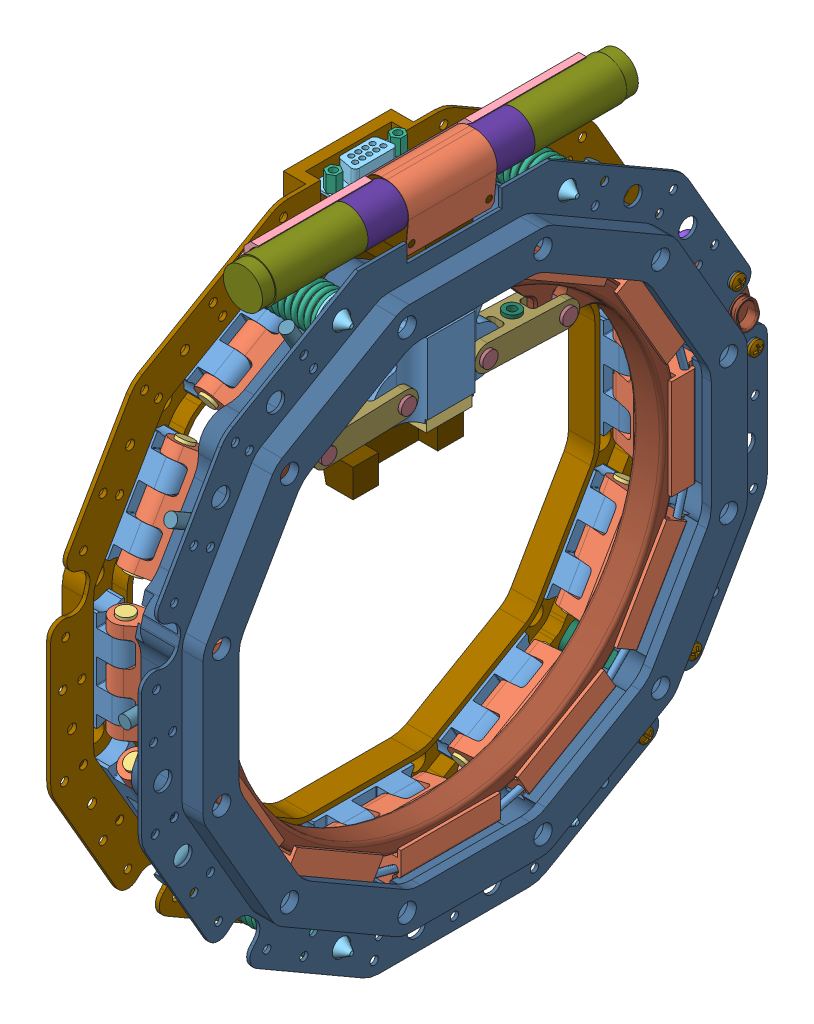
SolidWorks assembly T-01-00, configuration Default. Lengths in mm.
Overall size (53.34 255.61 245.22).
147 component instances, 37 part files, 0 mates.
Components (placement in the parent):
- 4000515 Rev A MLB 8.000-12 Assembly Simplified.STEP-1: 4000515 Rev A MLB 8.000-12 Assembly Simplified.STEP [Default] at origin size (53.34 255.61 245.22)
  - 4000519 MLB 8.000-12 Hinged Leaf Assembly SIMPLIFIED.STEP-1: 4000519 MLB 8.000-12 Hinged Leaf Assembly SIMPLIFIED.STEP [Default] at (4.318 84.9901 49.069) x (0 -0.5 0.866025) z (0 0.866025 0.5) size (40.89 39.6 18.1)
    - 4000391 Lower Hinge Link SIMPLIFIED.STEP-1: 4000391 Lower Hinge Link SIMPLIFIED.STEP [Default] at origin size (38.61 17.31 10.8)
    - 4000520 MLB 8.000-12 Upper Hinge Link SIMPLIFIED_Extrusion.STEP-1: 4000520 MLB 8.000-12 Upper Hinge Link SIMPLIFIED_Extrusion.STEP [Default] at (0 11.9126 0) size (38.61 33.09 18.1)
    - 4000369 Pin SIMPLIFIED.STEP-1: 4000369 Pin SIMPLIFIED.STEP [Default] at (0 11.9126 0) x (1 0 0) z (0 0 -1) size (40.89 6.31 6.31)
  - 4000307 Separation Spring Assembly SIMPLIFIED_Compressed.STEP-1: 4000307 Separation Spring Assembly SIMPLIFIED_Compressed.STEP [Default] at (10.16 -105.1143 -43.6767) x (0 -1 0) z (0 0 1) size (15.24 39.09 15.24)
    - 4000308 Separation Spring Lower Guide SIMPLIFIED.STEP-1: 4000308 Separation Spring Lower Guide SIMPLIFIED.STEP [Default] at origin size (15.24 31.34 15.24)
    - 4000309 Separation Spring Upper Guide SIMPLIFIED.STEP-1: 4000309 Separation Spring Upper Guide SIMPLIFIED.STEP [Default] at (0 2.286 0) size (15.24 36.8 15.24)
    - 0.60 OD x 0.072 Wire x 2.0 lg SST Spring SIMPLIFIED_Compressed.STEP-1: 0.60 OD x 0.072 Wire x 2.0 lg SST Spring SIMPLIFIED_Compressed.STEP [Default] at (0 3.1496 0) size (15.24 29.74 15.24)
    - 4000310 Separation Spring Pin SIMPLIFIED.STEP-1: 4000310 Separation Spring Pin SIMPLIFIED.STEP [Default] at (0 6.858 0) size (3.17 3.17 11.07)
  - 4000307 Separation Spring Assembly SIMPLIFIED_Compressed.STEP-2: 4000307 Separation Spring Assembly SIMPLIFIED_Compressed.STEP [Default] at (10.16 105.1143 -43.6767) x (0 -0.147249 -0.989099) z (0 -0.989099 0.147249) size (15.24 39.09 15.24)
    - 4000308 Separation Spring Lower Guide SIMPLIFIED.STEP-1: 4000308 Separation Spring Lower Guide SIMPLIFIED.STEP [Default] at origin size (15.24 31.34 15.24)
    - 4000309 Separation Spring Upper Guide SIMPLIFIED.STEP-1: 4000309 Separation Spring Upper Guide SIMPLIFIED.STEP [Default] at (0 2.286 0) size (15.24 36.8 15.24)
    - 0.60 OD x 0.072 Wire x 2.0 lg SST Spring SIMPLIFIED_Compressed.STEP-1: 0.60 OD x 0.072 Wire x 2.0 lg SST Spring SIMPLIFIED_Compressed.STEP [Default] at (0 3.1496 0) size (15.24 29.74 15.24)
    - 4000310 Separation Spring Pin SIMPLIFIED.STEP-1: 4000310 Separation Spring Pin SIMPLIFIED.STEP [Default] at (0 6.858 0) size (3.17 3.17 11.07)
  - 4000106 Lower Separation Connector SIMPLIFIED.STEP-1: 4000106 Lower Separation Connector SIMPLIFIED.STEP [Default] at (10.16 29.9775 -111.8774) x (0 -0.965926 -0.258819) z (0 0.258819 -0.965926) size (37.44 22.67 15.21)
    - 4000101 Lower Housing SIMPLIFIED.STEP-1: 4000101 Lower Housing SIMPLIFIED.STEP [Default] at origin size (37.44 21.64 15.21)
    - MS51957-14, 0.112-40 x 0.31 PNH Screw SIMPLIFIED.STEP-1: MS51957-14, 0.112-40 x 0.31 PNH Screw SIMPLIFIED.STEP [Default] at (-13.2461 4.1148 0) size (5.46 9.87 5.46)
    - MS51957-14, 0.112-40 x 0.31 PNH Screw SIMPLIFIED.STEP-2: MS51957-14, 0.112-40 x 0.31 PNH Screw SIMPLIFIED.STEP [Default] at (13.2461 4.1148 0) size (5.46 9.87 5.46)
    - NAS620C4, 0.115 x 0.209 x 0.032 Washer SIMPLIFIED.STEP-1: NAS620C4, 0.115 x 0.209 x 0.032 Washer SIMPLIFIED.STEP [Default] at (13.2461 1.27 0) size (5.31 0.81 5.31)
    - NAS620C4, 0.115 x 0.209 x 0.032 Washer SIMPLIFIED.STEP-2: NAS620C4, 0.115 x 0.209 x 0.032 Washer SIMPLIFIED.STEP [Default] at (-13.2461 1.27 0) size (5.31 0.81 5.31)
  - 4000107 Upper Separation Connector SIMPLIFIED.STEP-1: 4000107 Upper Separation Connector SIMPLIFIED.STEP [Default] at (49.8205 29.9775 -111.8774) x (0 0.965926 0.258819) z (0 0.258819 -0.965926) size (37.44 22.31 15.21)
    - 4000102 Upper Housing SIMPLIFIED.STEP-1: 4000102 Upper Housing SIMPLIFIED.STEP [Default] at (0 -5.8023 0) size (37.44 21.29 15.21)
    - MS51957-14, 0.112-40 x 0.31 PNH Screw SIMPLIFIED.STEP-1: MS51957-14, 0.112-40 x 0.31 PNH Screw SIMPLIFIED.STEP [Default] at (-13.2461 -1.6875 0) size (5.46 9.87 5.46)
    - MS51957-14, 0.112-40 x 0.31 PNH Screw SIMPLIFIED.STEP-2: MS51957-14, 0.112-40 x 0.31 PNH Screw SIMPLIFIED.STEP [Default] at (13.2461 -1.6875 0) x (0.987206 0 -0.159449) z (0.159449 0 0.987206) size (5.46 9.87 5.46)
    - NAS620C4, 0.115 x 0.209 x 0.032 Washer SIMPLIFIED.STEP-1: NAS620C4, 0.115 x 0.209 x 0.032 Washer SIMPLIFIED.STEP [Default] at (-13.2461 -4.5323 0) size (5.31 0.81 5.31)
    - NAS620C4, 0.115 x 0.209 x 0.032 Washer SIMPLIFIED.STEP-2: NAS620C4, 0.115 x 0.209 x 0.032 Washer SIMPLIFIED.STEP [Default] at (13.2461 -4.5323 0) size (5.31 0.81 5.31)
    - BG15L5-0.770-BEC-SOW-NKL-2, EMI Spring SIMPLIFIED.STEP-1: BG15L5-0.770-BEC-SOW-NKL-2, EMI Spring SIMPLIFIED.STEP [Default] at (0 -21.9313 0) size (35.89 2.03 13.67)
  - 4000383 Separation Switch Assembly SIMPLIFIED_Compressed.STEP-1: 4000383 Separation Switch Assembly SIMPLIFIED_Compressed.STEP [Default] at (44.0182 -78.5413 -78.5234) x (0 -0.707107 0.707107) z (0 -0.707107 -0.707107) size (33 44.21 11.81)
    - 4000350 Upper Switch Bracket SIMPLIFIED.STEP-1: 4000350 Upper Switch Bracket SIMPLIFIED.STEP [Default] at origin size (31.14 25.53 11.56)
    - MS24693-C27, 0.138-32 x 0.44 FLH Screw SIMPLIFIED.STEP-1: MS24693-C27, 0.138-32 x 0.44 FLH Screw SIMPLIFIED.STEP [Default] at (-6.35 20.701 11.4612) x (1 0 0) z (0 -1 0) size (6.35 11.11 6.35)
    - MS24693-C27, 0.138-32 x 0.44 FLH Screw SIMPLIFIED.STEP-2: MS24693-C27, 0.138-32 x 0.44 FLH Screw SIMPLIFIED.STEP [Default] at (6.35 20.701 11.4612) x (0.037732 -0.999288 0) z (-0.999288 -0.037732 0) size (6.35 11.11 6.35)
    - MS51957-14, 0.112-40 x 0.31 PNH Screw SIMPLIFIED.STEP-1: MS51957-14, 0.112-40 x 0.31 PNH Screw SIMPLIFIED.STEP [Default] at (13.2334 -4.1148 4.7625) x (-1 0 0) z (0 0 1) size (5.46 9.87 5.46)
    - MS51957-14, 0.112-40 x 0.31 PNH Screw SIMPLIFIED.STEP-2: MS51957-14, 0.112-40 x 0.31 PNH Screw SIMPLIFIED.STEP [Default] at (-13.2588 -4.1148 4.7625) x (0.837169 0 0.546944) z (0.546944 0 -0.837169) size (5.46 9.87 5.46)
    - NAS620C4, 0.115 x 0.209 x 0.032 Washer SIMPLIFIED.STEP-1: NAS620C4, 0.115 x 0.209 x 0.032 Washer SIMPLIFIED.STEP [Default] at (13.2334 -1.27 4.7625) x (-1 0 0) z (0 0 1) size (5.31 0.81 5.31)
    - NAS620C4, 0.115 x 0.209 x 0.032 Washer SIMPLIFIED.STEP-2: NAS620C4, 0.115 x 0.209 x 0.032 Washer SIMPLIFIED.STEP [Default] at (-13.2588 -1.27 4.7625) x (0.837169 0 0.546944) z (0.546944 0 -0.837169) size (5.31 0.81 5.31)
    - 65-401000 Switch SIMPLIFIED_Compressed Plunger.STEP-1: 65-401000 Switch SIMPLIFIED_Compressed Plunger.STEP [Default] at (0 23.0632 4.6355) size (21.59 38.91 9.78)
  - 4000519 MLB 8.000-12 Hinged Leaf Assembly SIMPLIFIED.STEP-2: 4000519 MLB 8.000-12 Hinged Leaf Assembly SIMPLIFIED.STEP [Default] at (4.318 49.069 84.9901) x (0 -0.866025 0.5) z (0 0.5 0.866025) size (40.89 39.6 18.1)
    - 4000391 Lower Hinge Link SIMPLIFIED.STEP-1: 4000391 Lower Hinge Link SIMPLIFIED.STEP [Default] at origin size (38.61 17.31 10.8)
    - 4000520 MLB 8.000-12 Upper Hinge Link SIMPLIFIED_Extrusion.STEP-1: 4000520 MLB 8.000-12 Upper Hinge Link SIMPLIFIED_Extrusion.STEP [Default] at (0 11.9126 0) size (38.61 33.09 18.1)
    - 4000369 Pin SIMPLIFIED.STEP-1: 4000369 Pin SIMPLIFIED.STEP [Default] at (0 11.9126 0) x (1 0 0) z (0 0 -1) size (40.89 6.31 6.31)
  - 4000519 MLB 8.000-12 Hinged Leaf Assembly SIMPLIFIED.STEP-3: 4000519 MLB 8.000-12 Hinged Leaf Assembly SIMPLIFIED.STEP [Default] at (4.318 0 98.1381) x (0 -1 0) z (0 0 1) size (40.89 39.6 18.1)
    - 4000391 Lower Hinge Link SIMPLIFIED.STEP-1: 4000391 Lower Hinge Link SIMPLIFIED.STEP [Default] at origin size (38.61 17.31 10.8)
    - 4000520 MLB 8.000-12 Upper Hinge Link SIMPLIFIED_Extrusion.STEP-1: 4000520 MLB 8.000-12 Upper Hinge Link SIMPLIFIED_Extrusion.STEP [Default] at (0 11.9126 0) size (38.61 33.09 18.1)
    - 4000369 Pin SIMPLIFIED.STEP-1: 4000369 Pin SIMPLIFIED.STEP [Default] at (0 11.9126 0) x (1 0 0) z (0 0 -1) size (40.89 6.31 6.31)
  - 4000519 MLB 8.000-12 Hinged Leaf Assembly SIMPLIFIED.STEP-4: 4000519 MLB 8.000-12 Hinged Leaf Assembly SIMPLIFIED.STEP [Default] at (4.318 -49.069 84.9901) x (0 -0.866025 -0.5) z (0 -0.5 0.866025) size (40.89 39.6 18.1)
    - 4000391 Lower Hinge Link SIMPLIFIED.STEP-1: 4000391 Lower Hinge Link SIMPLIFIED.STEP [Default] at origin size (38.61 17.31 10.8)
    - 4000520 MLB 8.000-12 Upper Hinge Link SIMPLIFIED_Extrusion.STEP-1: 4000520 MLB 8.000-12 Upper Hinge Link SIMPLIFIED_Extrusion.STEP [Default] at (0 11.9126 0) size (38.61 33.09 18.1)
    - 4000369 Pin SIMPLIFIED.STEP-1: 4000369 Pin SIMPLIFIED.STEP [Default] at (0 11.9126 0) x (1 0 0) z (0 0 -1) size (40.89 6.31 6.31)
  - 4000519 MLB 8.000-12 Hinged Leaf Assembly SIMPLIFIED.STEP-5: 4000519 MLB 8.000-12 Hinged Leaf Assembly SIMPLIFIED.STEP [Default] at (4.318 -84.9901 49.069) x (0 -0.5 -0.866025) z (0 -0.866025 0.5) size (40.89 39.6 18.1)
    - 4000391 Lower Hinge Link SIMPLIFIED.STEP-1: 4000391 Lower Hinge Link SIMPLIFIED.STEP [Default] at origin size (38.61 17.31 10.8)
    - 4000520 MLB 8.000-12 Upper Hinge Link SIMPLIFIED_Extrusion.STEP-1: 4000520 MLB 8.000-12 Upper Hinge Link SIMPLIFIED_Extrusion.STEP [Default] at (0 11.9126 0) size (38.61 33.09 18.1)
    - 4000369 Pin SIMPLIFIED.STEP-1: 4000369 Pin SIMPLIFIED.STEP [Default] at (0 11.9126 0) x (1 0 0) z (0 0 -1) size (40.89 6.31 6.31)
  - 4000519 MLB 8.000-12 Hinged Leaf Assembly SIMPLIFIED.STEP-6: 4000519 MLB 8.000-12 Hinged Leaf Assembly SIMPLIFIED.STEP [Default] at (4.318 -98.1381 0) x (0 0 -1) z (0 -1 0) size (40.89 39.6 18.1)
    - 4000391 Lower Hinge Link SIMPLIFIED.STEP-1: 4000391 Lower Hinge Link SIMPLIFIED.STEP [Default] at origin size (38.61 17.31 10.8)
    - 4000520 MLB 8.000-12 Upper Hinge Link SIMPLIFIED_Extrusion.STEP-1: 4000520 MLB 8.000-12 Upper Hinge Link SIMPLIFIED_Extrusion.STEP [Default] at (0 11.9126 0) size (38.61 33.09 18.1)
    - 4000369 Pin SIMPLIFIED.STEP-1: 4000369 Pin SIMPLIFIED.STEP [Default] at (0 11.9126 0) x (1 0 0) z (0 0 -1) size (40.89 6.31 6.31)
  - 4000519 MLB 8.000-12 Hinged Leaf Assembly SIMPLIFIED.STEP-7: 4000519 MLB 8.000-12 Hinged Leaf Assembly SIMPLIFIED.STEP [Default] at (4.318 -84.9901 -49.069) x (0 0.5 -0.866025) z (0 -0.866025 -0.5) size (40.89 39.6 18.1)
    - 4000391 Lower Hinge Link SIMPLIFIED.STEP-1: 4000391 Lower Hinge Link SIMPLIFIED.STEP [Default] at origin size (38.61 17.31 10.8)
    - 4000520 MLB 8.000-12 Upper Hinge Link SIMPLIFIED_Extrusion.STEP-1: 4000520 MLB 8.000-12 Upper Hinge Link SIMPLIFIED_Extrusion.STEP [Default] at (0 11.9126 0) size (38.61 33.09 18.1)
    - 4000369 Pin SIMPLIFIED.STEP-1: 4000369 Pin SIMPLIFIED.STEP [Default] at (0 11.9126 0) x (1 0 0) z (0 0 -1) size (40.89 6.31 6.31)
  - 4000519 MLB 8.000-12 Hinged Leaf Assembly SIMPLIFIED.STEP-8: 4000519 MLB 8.000-12 Hinged Leaf Assembly SIMPLIFIED.STEP [Default] at (4.318 -49.069 -84.9901) x (0 0.866025 -0.5) z (0 -0.5 -0.866025) size (40.89 39.6 18.1)
    - 4000391 Lower Hinge Link SIMPLIFIED.STEP-1: 4000391 Lower Hinge Link SIMPLIFIED.STEP [Default] at origin size (38.61 17.31 10.8)
    - 4000520 MLB 8.000-12 Upper Hinge Link SIMPLIFIED_Extrusion.STEP-1: 4000520 MLB 8.000-12 Upper Hinge Link SIMPLIFIED_Extrusion.STEP [Default] at (0 11.9126 0) size (38.61 33.09 18.1)
    - 4000369 Pin SIMPLIFIED.STEP-1: 4000369 Pin SIMPLIFIED.STEP [Default] at (0 11.9126 0) x (1 0 0) z (0 0 -1) size (40.89 6.31 6.31)
  - 4000519 MLB 8.000-12 Hinged Leaf Assembly SIMPLIFIED.STEP-9: 4000519 MLB 8.000-12 Hinged Leaf Assembly SIMPLIFIED.STEP [Default] at (4.318 0 -98.1381) x (0 1 0) z (0 0 -1) size (40.89 39.6 18.1)
    - 4000391 Lower Hinge Link SIMPLIFIED.STEP-1: 4000391 Lower Hinge Link SIMPLIFIED.STEP [Default] at origin size (38.61 17.31 10.8)
    - 4000520 MLB 8.000-12 Upper Hinge Link SIMPLIFIED_Extrusion.STEP-1: 4000520 MLB 8.000-12 Upper Hinge Link SIMPLIFIED_Extrusion.STEP [Default] at (0 11.9126 0) size (38.61 33.09 18.1)
    - 4000369 Pin SIMPLIFIED.STEP-1: 4000369 Pin SIMPLIFIED.STEP [Default] at (0 11.9126 0) x (1 0 0) z (0 0 -1) size (40.89 6.31 6.31)
  - 4000519 MLB 8.000-12 Hinged Leaf Assembly SIMPLIFIED.STEP-10: 4000519 MLB 8.000-12 Hinged Leaf Assembly SIMPLIFIED.STEP [Default] at (4.318 49.069 -84.9901) x (0 0.866025 0.5) z (0 0.5 -0.866025) size (40.89 39.6 18.1)
    - 4000391 Lower Hinge Link SIMPLIFIED.STEP-1: 4000391 Lower Hinge Link SIMPLIFIED.STEP [Default] at origin size (38.61 17.31 10.8)
    - 4000520 MLB 8.000-12 Upper Hinge Link SIMPLIFIED_Extrusion.STEP-1: 4000520 MLB 8.000-12 Upper Hinge Link SIMPLIFIED_Extrusion.STEP [Default] at (0 11.9126 0) size (38.61 33.09 18.1)
    - 4000369 Pin SIMPLIFIED.STEP-1: 4000369 Pin SIMPLIFIED.STEP [Default] at (0 11.9126 0) x (1 0 0) z (0 0 -1) size (40.89 6.31 6.31)
  - 4000519 MLB 8.000-12 Hinged Leaf Assembly SIMPLIFIED.STEP-11: 4000519 MLB 8.000-12 Hinged Leaf Assembly SIMPLIFIED.STEP [Default] at (4.318 84.9901 -49.069) x (0 0.5 0.866025) z (0 0.866025 -0.5) size (40.89 39.6 18.1)
    - 4000391 Lower Hinge Link SIMPLIFIED.STEP-1: 4000391 Lower Hinge Link SIMPLIFIED.STEP [Default] at origin size (38.61 17.31 10.8)
    - 4000520 MLB 8.000-12 Upper Hinge Link SIMPLIFIED_Extrusion.STEP-1: 4000520 MLB 8.000-12 Upper Hinge Link SIMPLIFIED_Extrusion.STEP [Default] at (0 11.9126 0) size (38.61 33.09 18.1)
    - 4000369 Pin SIMPLIFIED.STEP-1: 4000369 Pin SIMPLIFIED.STEP [Default] at (0 11.9126 0) x (1 0 0) z (0 0 -1) size (40.89 6.31 6.31)
  - 4000307 Separation Spring Assembly SIMPLIFIED_Compressed.STEP-3: 4000307 Separation Spring Assembly SIMPLIFIED_Compressed.STEP [Default] at (10.16 105.1143 43.6767) x (0 1 0) z (0 0 -1) size (15.24 39.09 15.24)
    - 4000308 Separation Spring Lower Guide SIMPLIFIED.STEP-1: 4000308 Separation Spring Lower Guide SIMPLIFIED.STEP [Default] at origin size (15.24 31.34 15.24)
    - 4000309 Separation Spring Upper Guide SIMPLIFIED.STEP-1: 4000309 Separation Spring Upper Guide SIMPLIFIED.STEP [Default] at (0 2.286 0) size (15.24 36.8 15.24)
    - 0.60 OD x 0.072 Wire x 2.0 lg SST Spring SIMPLIFIED_Compressed.STEP-1: 0.60 OD x 0.072 Wire x 2.0 lg SST Spring SIMPLIFIED_Compressed.STEP [Default] at (0 3.1496 0) size (15.24 29.74 15.24)
    - 4000310 Separation Spring Pin SIMPLIFIED.STEP-1: 4000310 Separation Spring Pin SIMPLIFIED.STEP [Default] at (0 6.858 0) size (3.17 3.17 11.07)
  - 4000307 Separation Spring Assembly SIMPLIFIED_Compressed.STEP-4: 4000307 Separation Spring Assembly SIMPLIFIED_Compressed.STEP [Default] at (10.16 -105.1143 43.6767) x (0 0.147249 0.989099) z (0 0.989099 -0.147249) size (15.24 39.09 15.24)
    - 4000308 Separation Spring Lower Guide SIMPLIFIED.STEP-1: 4000308 Separation Spring Lower Guide SIMPLIFIED.STEP [Default] at origin size (15.24 31.34 15.24)
    - 4000309 Separation Spring Upper Guide SIMPLIFIED.STEP-1: 4000309 Separation Spring Upper Guide SIMPLIFIED.STEP [Default] at (0 2.286 0) size (15.24 36.8 15.24)
    - 0.60 OD x 0.072 Wire x 2.0 lg SST Spring SIMPLIFIED_Compressed.STEP-1: 0.60 OD x 0.072 Wire x 2.0 lg SST Spring SIMPLIFIED_Compressed.STEP [Default] at (0 3.1496 0) size (15.24 29.74 15.24)
    - 4000310 Separation Spring Pin SIMPLIFIED.STEP-1: 4000310 Separation Spring Pin SIMPLIFIED.STEP [Default] at (0 6.858 0) size (3.17 3.17 11.07)
  - 4000433 F  Motor Bracket Assy Simple SIMPLIFIED.STEP-1: 4000433 F  Motor Bracket Assy Simple SIMPLIFIED.STEP [Default] at (4.318 98.5445 0) x (0 0 -1) z (0 -1 0) size (145.5 40.39 109.58)
    - 4000529 RE 16 Motor Assembly SIMPLIFIED.STEP-1: 4000529 RE 16 Motor Assembly SIMPLIFIED.STEP [Default] at (-40.2574 31.877 -27.4066) x (0 0.00997 -0.99995) z (1 0 0) size (16.16 16.16 55.94)
      - 4000535 RE16 Radial Pinion Hole SIMPLIFIED.STEP-1: 4000535 RE16 Radial Pinion Hole SIMPLIFIED.STEP [Default] at (0 0 7.9426) x (0 -1 0) z (0 0 1) size (16 16 40.44)
        - 4000530 RE 16 Motor SIMPLIFIED.STEP-1: 4000530 RE 16 Motor SIMPLIFIED.STEP [Default] x (0 1 0) z (0 0 1) size (16 16 40.44)
      - 4000532 GP 16 Gearhead SIMPLIFIED.STEP-1: 4000532 GP 16 Gearhead SIMPLIFIED.STEP [Default] at (0 0 23.4426) x (0.99995 -0.00997 0) z (0 0 1) size (16 16 15.5)
    - 4000529 RE 16 Motor Assembly SIMPLIFIED.STEP-2: 4000529 RE 16 Motor Assembly SIMPLIFIED.STEP [Default] at (40.2574 31.877 -27.4066) x (0 0.00997 0.99995) z (-1 0 0) size (16.16 16.16 55.94)
      - 4000535 RE16 Radial Pinion Hole SIMPLIFIED.STEP-1: 4000535 RE16 Radial Pinion Hole SIMPLIFIED.STEP [Default] at (0 0 7.9426) x (0 -1 0) z (0 0 1) size (16 16 40.44)
        - 4000530 RE 16 Motor SIMPLIFIED.STEP-1: 4000530 RE 16 Motor SIMPLIFIED.STEP [Default] x (0 1 0) z (0 0 1) size (16 16 40.44)
      - 4000532 GP 16 Gearhead SIMPLIFIED.STEP-1: 4000532 GP 16 Gearhead SIMPLIFIED.STEP [Default] at (0 0 23.4426) x (0.99995 -0.00997 0) z (0 0 1) size (16 16 15.5)
    - 4000394 Motor Bracket SIMPLIFIED.STEP-1: 4000394 Motor Bracket SIMPLIFIED.STEP [Default] at origin size (42.67 40.26 109.45)
    - 4000395 Sliding Tube SIMPLIFIED.STEP-1: 4000395 Sliding Tube SIMPLIFIED.STEP [Default] at (0 31.876 2.032) x (-1 0 0) z (0 0 -1) size (49.78 24 44.2)
    - 4000440 Gear Cover SIMPLIFIED.STEP-1: 4000440 Gear Cover SIMPLIFIED.STEP [Default] at (0 31.877 -27.4066) size (34.29 17.53 22.34)
    - 4000492 Deploy End Plate SIMPLIFIED.STEP-1: 4000492 Deploy End Plate SIMPLIFIED.STEP [Default] at (0 31.876 44.704) size (17.78 15.24 4.83)
    - 4000509 Motor Support SIMPLIFIED.STEP-1: 4000509 Motor Support SIMPLIFIED.STEP [Default] at (0 31.877 -27.4066) x (-1 0 0) z (0 0 -1) size (127 14.53 18.26)
    - HDC9S3000S DB-9 Socket Connector SIMPLIFIED.STEP-1: HDC9S3000S DB-9 Socket Connector SIMPLIFIED.STEP [Default] at (0 6.604 -17.018) x (-1 0 0) z (0 0 -1) size (30.81 12.55 16.99)
    - NAS1829C3C04, 0.112-40 MF Thread 0.187 x 0.25 Hex Standoff SIMPLIFIED.STEP-1: NAS1829C3C04, 0.112-40 MF Thread 0.187 x 0.25 Hex Standoff SIMPLIFIED.STEP [Default] at (-12.4968 6.604 -17.9324) x (-0.5 -0.866025 0) z (0.866025 -0.5 0) size (5.5 11.11 4.76)
    - NAS1829C3C04, 0.112-40 MF Thread 0.187 x 0.25 Hex Standoff SIMPLIFIED.STEP-2: NAS1829C3C04, 0.112-40 MF Thread 0.187 x 0.25 Hex Standoff SIMPLIFIED.STEP [Default] at (12.4968 6.604 -17.9324) x (-0.5 -0.866025 0) z (0.866025 -0.5 0) size (5.5 11.11 4.76)
    - NAS1352N06-6, 0.138-32 x 0.375 SHC Screw SIMPLIFIED.STEP-1: NAS1352N06-6, 0.138-32 x 0.375 SHC Screw SIMPLIFIED.STEP [Default] at (-6.35 17.145 -23.876) x (-0.89156 -0.452903 0) z (0.452903 -0.89156 0) size (5.74 13.03 5.74)
    - NAS1352N06-6, 0.138-32 x 0.375 SHC Screw SIMPLIFIED.STEP-2: NAS1352N06-6, 0.138-32 x 0.375 SHC Screw SIMPLIFIED.STEP [Default] at (6.35 17.145 -23.876) x (1 0 0) z (0 1 0) size (5.74 13.03 5.74)
    - NAS620C6, 0.143 x 0.267 x 0.032 Washer SIMPLIFIED.STEP-1: NAS620C6, 0.143 x 0.267 x 0.032 Washer SIMPLIFIED.STEP [Default] at (6.35 17.145 -20.3708) x (-0.988131 -0.153614 0) z (0.153614 -0.988131 0) size (6.78 0.81 6.78)
    - NAS620C6, 0.143 x 0.267 x 0.032 Washer SIMPLIFIED.STEP-2: NAS620C6, 0.143 x 0.267 x 0.032 Washer SIMPLIFIED.STEP [Default] at (-6.35 17.145 -19.558) x (-0.410963 0.911652 0) z (0.911652 0.410963 0) size (6.78 0.81 6.78)
  - 4000516 MLB 8.000-12 Lower Ring SIMPLIFIED.STEP-1: 4000516 MLB 8.000-12 Lower Ring SIMPLIFIED.STEP [Default] x (0 1 0) z (0 0 -1) size (242.3 10.16 242.3)
  - 4000517 MLB 8.000-12 Upper Ring SIMPLIFIED.STEP-1: 4000517 MLB 8.000-12 Upper Ring SIMPLIFIED.STEP [Default] at (53.34 0 0) x (0 1 0) z (0 0 -1) size (239.61 26.07 242.3)
  - 4000518 MLB 8.000-12 Retaining Ring SIMPLIFIED.STEP-1: 4000518 MLB 8.000-12 Retaining Ring SIMPLIFIED.STEP [Default] at (36.5506 0 0) x (0 1 0) z (0 0 -1) size (175.88 11.44 179.46)
  - 4000434 Link SIMPLIFIED_-0, 1.22_.STEP-1: 4000434 Link SIMPLIFIED_-0, 1.22_.STEP [Default] at (36.194 60.9197 31.2326) x (0 -0.034899 0.999391) z (0 0.999391 0.034899) size (40.64 12.19 9.65)
  - 4000434 Link SIMPLIFIED_-0, 1.22_.STEP-2: 4000434 Link SIMPLIFIED_-0, 1.22_.STEP [Default] at (36.194 60.9197 -31.2326) x (0 0.034899 0.999391) z (0 0.999391 -0.034899) size (40.64 12.19 9.65)
  - 4000496 Link Pin SIMPLIFIED.STEP-1: 4000496 Link Pin SIMPLIFIED.STEP [Default] at (36.194 60.379 46.7171) x (0 -0.95792 -0.287037) z (0 -0.287037 0.95792) size (5.99 14.71 5.99)
  - 4000496 Link Pin SIMPLIFIED.STEP-2: 4000496 Link Pin SIMPLIFIED.STEP [Default] at (36.194 61.4605 15.748) x (0 -0.720674 -0.693274) z (0 -0.693274 0.720674) size (5.99 14.71 5.99)
  - 4000496 Link Pin SIMPLIFIED.STEP-3: 4000496 Link Pin SIMPLIFIED.STEP [Default] at (36.194 61.4605 -15.748) x (0 -0.938985 -0.343957) z (0 -0.343957 0.938985) size (5.99 14.71 5.99)
  - 4000496 Link Pin SIMPLIFIED.STEP-4: 4000496 Link Pin SIMPLIFIED.STEP [Default] at (36.194 60.379 -46.7171) x (0 -0.870889 -0.49148) z (0 -0.49148 0.870889) size (5.99 14.71 5.99)
  - SSSD52 Spring Plunger SIMPLIFIED.STEP-1: SSSD52 Spring Plunger SIMPLIFIED.STEP [Default] at (36.5506 88.3088 46.6737) x (0 -0.866025 -0.5) z (0 -0.5 0.866025) size (22.23 4.83 4.83)
  - 5119K791, 0.125 x 0.250 Viton Tube SIMPLIFIED.STEP-1: 5119K791, 0.125 x 0.250 Viton Tube SIMPLIFIED.STEP [Default] at (36.194 56.8582 31.0907) x (-0.999391 0.001218 -0.034878) z (0.034899 0.034878 -0.998782) size (6.35 10.16 6.35)
  - 5119K791, 0.125 x 0.250 Viton Tube SIMPLIFIED.STEP-2: 5119K791, 0.125 x 0.250 Viton Tube SIMPLIFIED.STEP [Default] at (36.194 56.8582 -31.0907) x (-0.999391 -0.001218 -0.034878) z (0.034899 -0.034878 -0.998782) size (6.35 10.16 6.35)
  - NAS1102E3-8, 0.190-32 x 0.5 FLH Screw SIMPLIFIED.STEP-1: NAS1102E3-8, 0.190-32 x 0.5 FLH Screw SIMPLIFIED.STEP [Default] at (0.3124 101.8465 -10.16) x (0 -0.837169 0.546944) z (0 -0.546944 -0.837169) size (9.14 12.7 9.14)
  - NAS1102E3-8, 0.190-32 x 0.5 FLH Screw SIMPLIFIED.STEP-2: NAS1102E3-8, 0.190-32 x 0.5 FLH Screw SIMPLIFIED.STEP [Default] at (0.3124 85.3365 -10.16) x (0 -0.837169 0.546944) z (0 -0.546944 -0.837169) size (9.14 12.7 9.14)
  - NAS1102E3-8, 0.190-32 x 0.5 FLH Screw SIMPLIFIED.STEP-3: NAS1102E3-8, 0.190-32 x 0.5 FLH Screw SIMPLIFIED.STEP [Default] at (0.3124 101.8465 10.16) x (0 -0.837169 0.546944) z (0 -0.546944 -0.837169) size (9.14 12.7 9.14)
  - NAS1102E3-8, 0.190-32 x 0.5 FLH Screw SIMPLIFIED.STEP-4: NAS1102E3-8, 0.190-32 x 0.5 FLH Screw SIMPLIFIED.STEP [Default] at (0.3124 85.3365 10.16) x (0 -0.837169 0.546944) z (0 -0.546944 -0.837169) size (9.14 12.7 9.14)
  - MS51957-26, 0.138-32 x 0.25 PNH Screw SIMPLIFIED.STEP-1: MS51957-26, 0.138-32 x 0.25 PNH Screw SIMPLIFIED.STEP [Default] at (5.2832 -105.1143 -43.6767) x (0 -0.911634 -0.411003) z (0 0.411003 -0.911634) size (6.86 8.84 6.86)
  - SSSD52 Spring Plunger SIMPLIFIED.STEP-2: SSSD52 Spring Plunger SIMPLIFIED.STEP [Default] at (36.5506 53.1408 84.575) x (0 -0.5 -0.866025) z (0 -0.866025 0.5) size (22.23 4.83 4.83)
  - SSSD52 Spring Plunger SIMPLIFIED.STEP-3: SSSD52 Spring Plunger SIMPLIFIED.STEP [Default] at (36.5506 3.7338 99.8145) x (0 0 -1) z (0 -1 0) size (22.23 4.83 4.83)
  - SSSD52 Spring Plunger SIMPLIFIED.STEP-4: SSSD52 Spring Plunger SIMPLIFIED.STEP [Default] at (36.5506 -46.6737 88.3088) x (0 0.5 -0.866025) z (0 -0.866025 -0.5) size (22.23 4.83 4.83)
  - SSSD52 Spring Plunger SIMPLIFIED.STEP-5: SSSD52 Spring Plunger SIMPLIFIED.STEP [Default] at (36.5506 -84.575 53.1408) x (0 0.866025 -0.5) z (0 -0.5 -0.866025) size (22.23 4.83 4.83)
  - SSSD52 Spring Plunger SIMPLIFIED.STEP-6: SSSD52 Spring Plunger SIMPLIFIED.STEP [Default] at (36.5506 -99.8145 3.7338) x (0 1 0) z (0 0 -1) size (22.23 4.83 4.83)
  - SSSD52 Spring Plunger SIMPLIFIED.STEP-7: SSSD52 Spring Plunger SIMPLIFIED.STEP [Default] at (36.5506 -88.3088 -46.6737) x (0 0.866025 0.5) z (0 0.5 -0.866025) size (22.23 4.83 4.83)
  - SSSD52 Spring Plunger SIMPLIFIED.STEP-8: SSSD52 Spring Plunger SIMPLIFIED.STEP [Default] at (36.5506 -53.1408 -84.575) x (0 0.5 0.866025) z (0 0.866025 -0.5) size (22.23 4.83 4.83)
  - SSSD52 Spring Plunger SIMPLIFIED.STEP-9: SSSD52 Spring Plunger SIMPLIFIED.STEP [Default] at (36.5506 -3.7338 -99.8145) x (0 0 1) z (0 1 0) size (22.23 4.83 4.83)
  - SSSD52 Spring Plunger SIMPLIFIED.STEP-10: SSSD52 Spring Plunger SIMPLIFIED.STEP [Default] at (36.5506 46.6737 -88.3088) x (0 -0.5 0.866025) z (0 0.866025 0.5) size (22.23 4.83 4.83)
  - SSSD52 Spring Plunger SIMPLIFIED.STEP-11: SSSD52 Spring Plunger SIMPLIFIED.STEP [Default] at (36.5506 84.575 -53.1408) x (0 -0.866025 0.5) z (0 0.5 0.866025) size (22.23 4.83 4.83)
  - MS51957-14, 0.112-40 x 0.31 PNH Screw SIMPLIFIED.STEP-1: MS51957-14, 0.112-40 x 0.31 PNH Screw SIMPLIFIED.STEP [Default] at (13.0048 -91.2663 -72.5335) x (0 0.985398 0.170268) z (0 0.170268 -0.985398) size (5.46 9.87 5.46)
  - MS51957-14, 0.112-40 x 0.31 PNH Screw SIMPLIFIED.STEP-2: MS51957-14, 0.112-40 x 0.31 PNH Screw SIMPLIFIED.STEP [Default] at (13.0048 -72.5335 -91.2663) x (0 0.985398 0.170268) z (0 0.170268 -0.985398) size (5.46 9.87 5.46)
  - NAS620C4, 0.115 x 0.209 x 0.032 Washer SIMPLIFIED.STEP-1: NAS620C4, 0.115 x 0.209 x 0.032 Washer SIMPLIFIED.STEP [Default] at (10.16 -91.2663 -72.5335) x (0 -1 0) z (0 0 1) size (5.31 0.81 5.31)
  - NAS620C4, 0.115 x 0.209 x 0.032 Washer SIMPLIFIED.STEP-2: NAS620C4, 0.115 x 0.209 x 0.032 Washer SIMPLIFIED.STEP [Default] at (10.16 -72.5335 -91.2663) x (0 -1 0) z (0 0 1) size (5.31 0.81 5.31)
  - 4000351 Lower Switch Bracket SIMPLIFIED.STEP-1: 4000351 Lower Switch Bracket SIMPLIFIED.STEP [Default] at (8.636 -81.891 -81.9089) x (0 0.707107 -0.707107) z (0 0.707107 0.707107) size (31.14 6.68 6.6)
  - MS51957-26, 0.138-32 x 0.25 PNH Screw SIMPLIFIED.STEP-2: MS51957-26, 0.138-32 x 0.25 PNH Screw SIMPLIFIED.STEP [Default] at (5.2832 -105.1143 43.6767) x (0 0.911634 0.411003) z (0 -0.411003 0.911634) size (6.86 8.84 6.86)
  - MS51957-26, 0.138-32 x 0.25 PNH Screw SIMPLIFIED.STEP-3: MS51957-26, 0.138-32 x 0.25 PNH Screw SIMPLIFIED.STEP [Default] at (5.2832 105.1143 43.6767) x (0 0.911634 0.411003) z (0 -0.411003 0.911634) size (6.86 8.84 6.86)
  - MS51957-26, 0.138-32 x 0.25 PNH Screw SIMPLIFIED.STEP-4: MS51957-26, 0.138-32 x 0.25 PNH Screw SIMPLIFIED.STEP [Default] at (5.2832 105.1143 -43.6767) x (0 0.911634 0.411003) z (0 -0.411003 0.911634) size (6.86 8.84 6.86)
  - NAS620C6, 0.143 x 0.267 x 0.032 Washer SIMPLIFIED.STEP-1: NAS620C6, 0.143 x 0.267 x 0.032 Washer SIMPLIFIED.STEP [Default] at (7.8232 -105.1143 43.6767) x (0 0.381849 -0.924225) z (0 0.924225 0.381849) size (6.78 0.81 6.78)
  - NAS620C6, 0.143 x 0.267 x 0.032 Washer SIMPLIFIED.STEP-2: NAS620C6, 0.143 x 0.267 x 0.032 Washer SIMPLIFIED.STEP [Default] at (7.8232 105.1143 43.6767) x (0 0.381849 -0.924225) z (0 0.924225 0.381849) size (6.78 0.81 6.78)
  - NAS620C6, 0.143 x 0.267 x 0.032 Washer SIMPLIFIED.STEP-3: NAS620C6, 0.143 x 0.267 x 0.032 Washer SIMPLIFIED.STEP [Default] at (7.8232 105.1143 -43.6767) x (0 0.381849 -0.924225) z (0 0.924225 0.381849) size (6.78 0.81 6.78)
  - 4000629 8inch Leaf Retaining Cordsimple_8.000-12.STEP-1: 4000629 8inch Leaf Retaining Cordsimple_8.000-12.STEP [Default] at (41.6306 0.1173 0) x (0 1 0) z (0 0 1) size (184.68 2.36 188.28)
